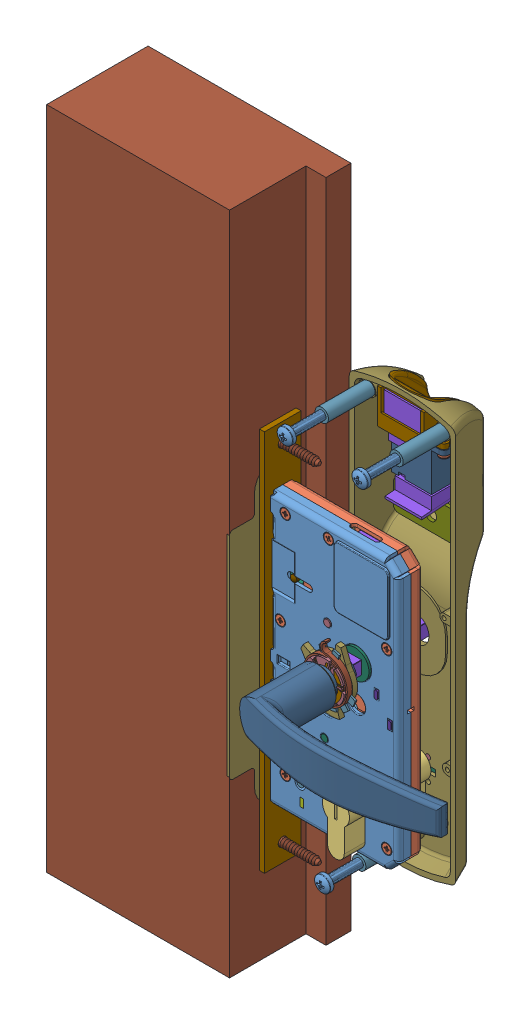
SolidWorks assembly serrure, configuration Défaut. Lengths in mm.
Overall size (189.43 263.51 140.02).
129 component instances, 74 part files, 37 mates.
Components (placement in the parent):
- porte-1: porte [Défaut] at origin size (273.47 400 77.87)
  - capteur-1: capteur [Défaut] at (-59.4622 -33.5309 -3.2336) x (0.307692 -0.951486 0) z (-0.951486 -0.307692 0) size (14.18 5.77 12.92)
    - piece26-1: piece26 [Défaut] at (1.6738 0.6186 2.775) size (12.75 5.77 7.15)
    - piece 28-1: piece 28 [Défaut] at (1.6738 0.6186 0.775) size (12.75 5.77 5.95)
    - piece27-2: piece27 [Défaut] at (-0.2012 0.6186 2.975) size (1 2.8 4.5)
    - piece29-1: piece29 [Défaut] at (-3.3489 0.6186 5.3357) x (0.986417 0 0.164259) z (-0.164259 0 0.986417) size (13.3 5.06 1.9)
  - Assemblage9-1: Assemblage9 [Défaut] at (-68.5121 32.669 3.5) x (0 1 0) z (0 0 -1) size (37.07 29 14.01)
    - Pièce31-1: Pièce31 [Défaut] at (-136.852 -20.6482 -3) size (37.07 29 6.5)
    - Assemblage8-1: Assemblage8 [Défaut] at (10.8904 0.9488 3.6462) x (0 0 1) z (0 1 0) size (12.77 25.8 12.77)
      - piece 33-1: piece 33 [Défaut] at (-0.2667 2.2913 0) size (11 9 11)
      - piece32-1: piece32 [Défaut] at (-0.2667 2.2913 0) x (-0.176766 0 0.984253) z (-0.984253 0 -0.176766) size (11 19.8 11)
    - Pièce30-1: Pièce30 [Défaut] at (-136.852 22.3518 10) x (1 0 0) z (0 0 -1) size (37.07 29 14)
  - tetiere-1: tetiere [Défaut] at (-124.6604 -27.8986 -47.7834) x (0 0 -1) z (1 0 0) size (22 230 25.2)
    - tetiere-1: tetiere [Défaut] at (-47.7834 3.4752 0) size (22 230 6)
    - Pièce37-1: Pièce37 [Défaut] at (-8.0012 83.4752 -19.368) x (1 0 0) z (0 -1 0) size (11 12 10)
    - Pièce37-2: Pièce37 [Défaut] at (-8.0012 -52.5248 -19.368) x (1 0 0) z (0 -1 0) size (11 12 10)
    - vis F90 M5-25-1: vis F90 M5-25 [PreviewCfg] at (-47.7834 107.4752 -1.3) x (0 0 1) z (-1 0 0) size (25 9.3 9.3)
    - vis F90 M5-25-2: vis F90 M5-25 [PreviewCfg] at (-47.7834 -100.5248 -1.3) x (0 0 1) z (-1 0 0) size (25 9.3 9.3)
  - Assemblage5-1: Assemblage5 [Défaut] at (-67.1198 -31.1461 -5) x (0 1 0) z (0 0 1) size (150 70 16.5)
    - Pièce20-1: Pièce20 [Défaut] at (81.7227 21.0405 -3.5) x (0 0 1) z (-1 0 0) size (14 6 6)
    - Pièce20-2: Pièce20 [Défaut] at (41.7227 -13.9595 -3.5) x (0 0 1) z (-1 0 0) size (14 6 6)
    - Pièce20-3: Pièce20 [Défaut] at (24.7227 50.0405 -3.5) x (0 0 1) z (-1 0 0) size (14 6 6)
    - Pièce20-4: Pièce20 [Défaut] at (11.2227 11.9905 -3.5) x (0 0 1) z (-0.071229 0.99746 0) size (14 6 6)
    - Pièce20-5: Pièce20 [Défaut] at (-62.2773 -13.9595 -3.5) x (0 0 1) z (-1 0 0) size (14 6 6)
    - Pièce21-1: Pièce21 [Défaut] at (37.7227 21.5405 -3.5) x (0 0 1) z (-1 0 0) size (16.4 6 6)
    - Pièce23-1: Pièce23 [Défaut] at (-54.2773 38.0405 -3.5) x (0 0 1) z (-1 0 0) size (16 6 6)
    - Pièce22-2: Pièce22 [Défaut] at (-23.2773 23.5405 -3.5) x (0 0 1) z (-0.988921 -0.148442 0) size (16 6 6)
    - Pièce24-1: Pièce24 [Défaut] at (3.7227 19.5405 3) x (-1 0 0) z (0 0 -1) size (10 9 9.5)
    - Pièce25-1: Pièce25 [Défaut] at (-74.2773 -20.9595 -0.5) size (28 10 16)
    - Pièce38-1: Pièce38 [Défaut] at (65.7227 21.0405 -3.5) x (0 0 1) z (-1 0 0) size (9 6 6)
  - Pièce18-1: Pièce18 [Défaut] at (-46.1604 57.5766 7.5) x (0 -1 0) z (0 0 -1) size (163.01 77.21 8.5)
  - vis1-1: vis1 [ISO 7046-1 - M3 x 6 - Z --- 6C] at (-114.1604 50.5766 -7.5) x (0 0 1) z (0 -1 0) size (6 5.5 5.5)
  - vis1-2: vis1 [ISO 7046-1 - M3 x 6 - Z --- 6C] at (-114.1604 -85.4234 -7.5) x (0 0 1) z (0.484646 -0.87471 0) size (6 5.5 5.5)
  - vis1-3: vis1 [ISO 7046-1 - M3 x 6 - Z --- 6C] at (-53.1604 10.5766 7.5) x (0 0 -1) z (0 1 0) size (6 5.5 5.5)
  - vis1-4: vis1 [ISO 7046-1 - M3 x 6 - Z --- 6C] at (-53.1604 -93.4234 7.5) x (0 0 -1) z (0 1 0) size (6 5.5 5.5)
  - vis1-5: vis1 [ISO 7046-1 - M3 x 6 - Z --- 6C] at (-88.1604 50.5766 7.5) x (0 0 -1) z (-0.949467 0.313867 0) size (6 5.5 5.5)
  - vis1-6: vis1 [ISO 7046-1 - M3 x 6 - Z --- 6C] at (-117.1604 -6.4234 7.5) x (0 0 -1) z (0 1 0) size (6 5.5 5.5)
  - vis1-7: vis1 [ISO 7046-1 - M3 x 6 - Z --- 6C] at (-114.1604 -85.4234 7.5) x (0 0 -1) z (0 1 0) size (6 5.5 5.5)
  - vis1-8: vis1 [ISO 7046-1 - M3 x 6 - Z --- 6C] at (-114.1604 50.5766 7.5) x (0 0 -1) z (0 1 0) size (6 5.5 5.5)
  - vis1-9: vis1 [ISO 7046-1 - M3 x 6 - Z --- 6C] at (-79.1104 -19.9234 7.5) x (0 0 -1) z (0 1 0) size (6 5.5 5.5)
  - vis2-1: vis2 [ISO 7045 - M2 x 8 - Z --- 8N] at (-61.1604 -32.4234 1.87) x (0 0 -1) z (0 1 0) size (9.57 4 4)
  - vis2-2: vis2 [ISO 7045 - M2 x 8 - Z --- 8N] at (-59.1604 -38.6081 1.87) x (0 0 -1) z (0 1 0) size (9.57 4 4)
  - vis5-1: vis5 [ISO 7046-1 - M2 x 4 - Z --- 4C] at (-78.6604 46.8507 -3.4464) x (0 0 -1) z (0.839549 0.543284 0) size (5 3.8 3.8)
  - Pièce35-1: Pièce35 [Défaut] at (-90.6604 -54.4234 0.5) x (0 1 0) z (0 0 1) size (11 11 0.5)
  - Pièce6-1: Pièce6 [Défaut] at (-90.6604 -54.4234 -2.5) x (0.802376 0.596819 0) z (0 0 1) size (8 8 3)
  - Pièce13-1: Pièce13 [Défaut] at (-59.3625 -101.9234 0) size (24 12 15)
  - Assemblage a3-2: Assemblage a3 [Défaut] at (-71.1604 89.3876 -33.9686) x (0 1 0) z (-1 0 0) size (249.51 77.87 69.84)
    - pièce a25-1: pièce a25 [Défaut] at (28.1889 -12.4686 0) size (57.24 25.6 22)
    - pièce a23-1: pièce a23 [Défaut] at (29.1889 -14.9686 0) x (-1 0 0) z (0 0 -1) size (32.42 29.23 38)
    - pièce a24-2: pièce a24 [Défaut] at (-4.8111 7.5314 0) x (0 0 1) z (1 0 0) size (42 16 26)
    - piece a27-1: piece a27 [B18.6.7M - M3 x 0.5 x 6 Type I Cross Recessed FHMS --6N] at (3.4889 -5.4686 -16.5) size (7 5.5 5.5)
    - piece a27-2: piece a27 [B18.6.7M - M3 x 0.5 x 6 Type I Cross Recessed FHMS --6N] at (3.4889 -5.4686 16.5) x (1 0 0) z (0 0 -1) size (7 5.5 5.5)
    - Assemblage a1-1: Assemblage a1 [Défaut] at (-110.8532 -13.9686 -2.8343) x (0 0 1) z (0 1 0) size (69.84 249.51 54.23)
      - piece a1-1: piece a1 [Défaut] at (2.8343 16.0422 0) size (69.84 249.51 28.23)
      - pièce a9-4: pièce a9 [Défaut] at (-3.5296 -48.0939 9) size (3 3 2)
      - pièce a9-5: pièce a9 [Défaut] at (0.505 -63.1512 9) x (-0.5 0.866025 0) z (0 0 1) size (3 3 2)
      - pièce a9-6: pièce a9 [Défaut] at (11.5277 -52.1285 9) x (-0.5 -0.866025 0) z (0 0 1) size (3 3 2)
      - pièce a8-1: pièce a8 [Défaut] at (25.3343 133.0422 8) x (0 0 -1) z (1 0 0) size (34 8 8)
      - pièce a8-2: pièce a8 [Défaut] at (-19.6657 133.0422 8) x (0 0 -1) z (1 0 0) size (34 8 8)
      - pièce a27-1: pièce a27 [Défaut] at (2.8343 -54.4578 11) size (22 22 2.5)
      - pièce a8-3: pièce a8 [Défaut] at (2.8343 -88.9578 8) x (0 0 -1) z (1 0 0) size (34 8 8)
      - pièce a26-1: pièce a26 [Défaut] at (2.8343 71.0422 17) size (45 18 2)
      - piece a20-1: piece a20 [ISO 7045 - M3 x 8 - Z --- 8N] at (-15.6657 104.0422 16.1) x (0 0 1) z (-1 0 0) size (10.35 5.6 5.6)
      - piece a20-2: piece a20 [ISO 7045 - M3 x 8 - Z --- 8N] at (21.3343 104.0422 16.1) x (0 0 1) z (-1 0 0) size (10.35 5.6 5.6)
      - piece a21-1: piece a21 [ISO 7045 - M3 x 6 - Z --- 6N] at (-15.6657 71.0422 14.6) x (0 0 1) z (-1 0 0) size (8.35 5.6 5.6)
      - piece a21-2: piece a21 [ISO 7045 - M3 x 6 - Z --- 6N] at (21.3343 71.0422 14.6) x (0 0 1) z (-1 0 0) size (8.35 5.6 5.6)
    - vis4-1: vis4 [ISO 7045 - M5 x 45 - Z --- 45N] at (22.1889 -63.6686 -22.5) x (0 1 0) z (0.065029 0 0.997883) size (48.63 9.5 9.5)
    - vis4-2: vis4 [ISO 7045 - M5 x 45 - Z --- 45N] at (22.1889 -63.6686 22.5) x (0 1 0) z (0.065029 0 0.997883) size (48.63 9.5 9.5)
    - vis4-3: vis4 [ISO 7045 - M5 x 45 - Z --- 45N] at (-199.8111 -63.6686 0) x (0 1 0) z (0.065029 0 0.997883) size (48.63 9.5 9.5)
  - porte-2: porte [Défaut] at (23.8396 10.5766 0) size (273.47 400 40) (hidden)
  - Pièce19-1: Pièce19 [Défaut] at (-46.1604 -105.4234 -7.5) x (0 1 0) z (0 0 1) size (163.01 77.21 11)
  - cylindre europeen-1: cylindre europeen [Défaut] at (-71.1604 -75.9234 -2.5) x (-1 0 0) z (0 0 -1) size (16.3 33.65 49)
  - vis F90 M5-60-1: vis F90 M5-60 [PreviewCfg] at (-125.9604 -95.4234 0) size (60 9.3 9.3)
  - axe moteur-1: axe moteur [Défaut] at (-65.5909 21.3931 -13.2202) x (-0.984609 0 -0.17477) z (0.17477 0 -0.984609) size (5.26 10.46 5.13)
  - poussoir-1: poussoir [Défaut] at (-46.1604 -106.9762 -2.2801) x (0 1 0) z (0 0 1) size (21.08 22 6)
- poignee exterieure-1: poignee exterieure [Défaut] at (0.1686 -5.7947 -1) x (0.996714 -0.081007 0) z (0 0 1) size (143.89 49.43 175.53)
  - pièce a3-1: pièce a3 [Défaut] at (-71.1604 -5.4234 -28.5) x (-1 0 0) z (0 0 -1) size (21 21 1) (hidden)
  - pièce a3-3: pièce a3 [Défaut] at (-71.1604 -5.4234 -33.5) x (0.888915 -0.458071 0) z (0 0 1) size (21 21 1) (hidden)
  - bequille-1: bequille [Défaut] at (-71.1246 -5.4081 -34) x (-0.079085 0.996868 0) z (0 0 1) size (34.63 120.11 70.52) (hidden)
  - pièce a16-1: pièce a16 [Défaut] at (-71.1246 -5.4081 -25) x (-0.999944 -0.010542 0) z (0 0 -1) size (31.16 38.76 3.06) (hidden)
  - pièce a5-1: pièce a5 [Défaut] at (-70.7945 -5.1928 -23.5) x (-0.082996 -0.99655 0) z (0 0 -1) size (33.22 26.47 3.09) (hidden)
  - pièce a7-1: pièce a7 [Défaut] at (-71.1246 -5.4081 -21.5) x (-0.986222 0.165429 0) z (0 0 -1) size (28 32 0.5) (hidden)
  - pièce a4-1: pièce a4 [Défaut] at (-71.1246 -5.4081 -18.5) x (-0.884093 0.467311 0) z (0 0 -1) size (23.6 24 3) (hidden)
  - Pièce16-1: Pièce16 [Défaut] at (-71.1246 -5.4081 -7) x (0 0 1) z (0.996868 0.079085 0) size (12.5 20 20)
  - carre-1: carre [Défaut] at (-71.1246 -5.4081 -53) x (-0.996868 -0.079085 0) z (0 0 -1) size (8.02 8 52)
  - poignee interieure-1: poignee interieure [Défaut] at (-0.6374 5.762 0) x (0.996714 0.081007 0) z (0 0 1) size (141.35 41.34 91.02)
    - pièce a3-1: pièce a3 [Défaut] at (-71.1604 -5.4234 32) size (21 21 1)
    - bequille-1: bequille [Défaut] at (-71.0969 -5.4234 32.5) x (0 -1 0) z (0 0 -1) size (34.63 120.11 70.52)
    - pièce a5-1: pièce a5 [Défaut] at (-71.9887 -5.499 25.5) x (0.053548 -0.998565 0) z (0 0 1) size (33.22 26.47 3.09)
    - pièce a16-1: pièce a16 [Défaut] at (-71.0969 -5.4234 24) x (-0.999972 -0.007518 0) z (0 0 -1) size (31.16 38.76 3.06)
    - pièce a4-1: pièce a4 [Défaut] at (-71.0969 -5.4234 28) x (0.409792 0.912179 0) z (0 0 -1) size (23.6 24 3)
    - pièce a7bis-1: pièce a7bis [Défaut] at (-71.0969 -5.4234 25) x (-0.969106 0.246645 0) z (0 0 -1) size (28 32 1)
    - pièce a3-2: pièce a3 [Défaut] at (-71.0969 -5.4234 27.5) size (21 21 1)
    - carre-1: carre [Défaut] at (-71.0969 -5.4234 51.5) size (8.02 8 52)
    - Assemblage4-1: Assemblage4 [Défaut] at (-71.1604 -5.4234 1.3) size (52.31 35.86 13.6)
      - Pièce14-1: Pièce14 [Défaut] at origin size (52.31 34.86 13.6)
      - ressort1-1: ressort1 [Défaut] at (0 11 0) x (-0.996138 0 -0.087798) z (0 1 0) size (5.8 6.7 6.99)
      - Pièce15-1: Pièce15 [Défaut] at origin size (17.38 4.41 10.6)
    - axe de noix-1: axe de noix [Défaut] at (-71.1604 0.3833 1.3) x (0 1 0) z (0 0 -1) size (15.4 6 6)
- verrouilleur-1: verrouilleur [Défaut] at (-129.1604 -27.4234 5) x (1 0 0) z (0 1 0) size (30.05 12 6)
- plaque-1: plaque [Défaut] at (-84.6824 -30.3877 5.6) x (0 -1 0) z (0 0 -1) size (115.86 55.31 11.5)
  - Pièce8-1: Pièce8 [Défaut] at (-51.9489 -2.022 0) size (115.86 54.87 2.63)
  - Pièce9-1: Pièce9 [Défaut] at (-15.5889 16.4069 10) x (0 0 -1) z (1 0 0) size (11 6 6)
  - Pièce9-2: Pièce9 [Défaut] at (60.9111 5.978 10) x (0 0 -1) z (1 0 0) size (11 6 6)
  - Pièce9-3: Pièce9 [Défaut] at (40.1491 -25.25 10) x (0 0 -1) z (0.486722 0.873557 0) size (11 6 6)
  - Pièce10-1: Pièce10 [Défaut] at (5.0511 3.978 -1.5) x (0 0 1) z (-1 0 0) size (4.5 8 8)
- pene dormant-1: pene dormant [Défaut] at (-113.0755 -51.7425 -1) x (1 0 0) z (0 0 -1) size (62 37 12)
  - Pièce11-1: Pièce11 [Défaut] at (-30.5849 -8.319 -1.5) size (62 37 9)
  - Pièce12-1: Pièce12 [Défaut] at (24.4151 -8.319 -5.5) x (0 0 1) z (-0.906877 -0.421394 0) size (12 5 5)
- pene lançant-1: pene lançant [Défaut] at (-116.6048 19.0766 -2.0131) x (1 0 0) z (0 -1 0) size (40.25 15.66 28)
  - Pièce5-1: Pièce5 [Défaut] at (-12.8916 -3.2369 -4) size (32 11 8)
  - Pièce4-1: Pièce4 [Défaut] at (-6.8916 2.2631 10.5) x (0 0 -1) z (1 0 0) size (21 6 6)
  - axe de noix-1: axe de noix [Défaut] at (7.1084 -5.2369 0) x (0 1 0) z (0 0 1) size (15.4 6 6)
  - Pièce6-1: Pièce6 [Défaut] at (7.1084 4.1631 0) x (0.982348 0 0.187064) z (0 1 0) size (8 8 3)
  - Pièce3-3: Pièce3 [Défaut] at (-6.8916 2.2631 -14) x (0.984808 -0.173648 0) z (0 0 1) size (19 11 14)
  - Pièce3-4: Pièce3 [Défaut] at (-6.8916 2.2631 14) x (0.984808 0.173648 0) z (0 0 -1) size (19 11 14)
- guide ressort-1: guide ressort [Défaut] at (-54.3814 1.7305 0) x (0 0 1) z (-0.999945 -0.010466 0) size (11 27.12 1.5)
- ressorts-1: ressorts [Défaut] at (-205.5407 -154.3869 208.4697) x (1 0 0) z (0 0 -1) size (76.49 152.32 18.47) (hidden)
  - ressort2-2: ressort2 [Défaut] at (106.6303 -126.9635 210.4697) x (0 0 1) z (1 0 0) size (6 6.93 15.69)
  - ressort3 position fermée-1: ressort3 position fermée [Défaut] at (147.4246 -79.0467 210.9697) x (0 0 -1) z (0.264302 0.96444 0) size (9.52 9.47 31.36)
  - ressort6 position fermée-2: ressort6 position fermée [Défaut] at (151.4017 -132.9478 208.4697) x (0.99055 -0.010368 -0.13676) z (-0.010466 -0.999945 0) size (8.58 8.62 23.12)
  - ressort4 position fermée-1: ressort4 position fermée [Défaut] at (117.3803 -188.9635 213.3697) x (-0.904323 -0.426848 0) z (0 0 -1) size (11.11 43.12 16.27)
  - ressort 5 position fermée-1: ressort 5 position fermée [Défaut] at (100.3803 -68.9635 212.9697) x (0.995167 0.098198 0) z (0 0 -1) size (25.36 30.87 7.5)
- chambranle-1: chambranle [Défaut] at (290.2615 1279.4527 -72.4696) size (122 400 61)
  - cadre dormant2-1: cadre dormant2 [Défaut] at (-419.4219 -1306.8762 77.4696) x (0 1 0) z (-1 0 0) size (400 61 122)
  - gache-1: gache [Défaut] at (-420.9219 -1306.8762 77.4696) x (0 -1 0) z (1 0 0) size (178.25 40 1.5)
  - vis F90 M3-25-1: vis F90 M3-25 [PreviewCfg] at (-419.4219 -1220.3762 70.9696) x (-1 0 0) z (0 1 0) size (20 5.5 5.5)
  - vis F90 M3-25-2: vis F90 M3-25 [PreviewCfg] at (-419.4219 -1286.3762 70.9696) x (-1 0 0) z (0 1 0) size (20 5.5 5.5)
  - vis F90 M3-25-3: vis F90 M3-25 [PreviewCfg] at (-419.4219 -1379.6262 70.9696) x (-1 0 0) z (0 1 0) size (20 5.5 5.5)
Mates (geometry in assembly coordinates):
- Coïncidente1: coincident anti-aligned: plane of porte-1/tetiere-1/tetiere-1 through (-126.1614 -25.4234 -5.5) normal (0 0 1); plane of verrouilleur-1 through (-121.1604 -24.4234 -5.5) normal (0 0 -1)
- Coïncidente2: coincident anti-aligned: plane of porte-1/tetiere-1/tetiere-1 through (-126.1614 -24.4234 5.5) normal (0 -1 0); plane of verrouilleur-1 through (-105.7938 -24.4234 16.2147) normal (0 1 0)
- Coïncidente4: coincident anti-aligned: plane of porte-1/tetiere-1/tetiere-1 through (-126.1614 -43.4234 3.5) normal (0 0 -1); plane of pene dormant-1/Pièce11-1 through (-143.6604 -76.4234 3.5) normal (0 0 1)
- Coïncidente5: coincident anti-aligned: plane of porte-1/tetiere-1/tetiere-1 through (-126.1614 -43.4234 2.5) normal (0 -1 0); plane of pene dormant-1/Pièce11-1 through (-122.6604 -43.4234 -5.5) normal (0 1 0)
- Coaxiale2: concentric aligned: cylinder of porte-1/Assemblage a3-2/Assemblage a1-1/piece a1-1 through (-71.1604 -5.4234 -19.999) axis (0 0 -1) radius 8; cylinder of poignee exterieure-1/Pièce16-1 through (-71.1604 -5.4234 -66.8035) axis (0 0 -1) radius 7.5
- Coïncidente12: coincident anti-aligned: plane of porte-1/tetiere-1/tetiere-1 through (-126.1614 30.0766 5.75) normal (0 0 -1); plane of pene lançant-1/Pièce5-1 through (-129.4964 15.0766 5.75) normal (0 0 1)
- Tangent2: tangent anti-aligned: cylinder of porte-1/Assemblage5-1/Pièce21-1 through (-88.6604 6.5766 7.9) axis (0 0 1) radius 2; plane of plaque-1/Pièce8-1 through (-86.6604 6.5612 5.6) normal (-1 0 0)
- Distance1: distance = 1.5 mm anti-aligned: plane of verrouilleur-1 through (-102.1604 -24.4234 1.5) normal (0 0 1); plane of plaque-1/Pièce8-1 through (-102.6505 7.1892 3) normal (0 0 -1)
- Tangent5: tangent anti-aligned: cylinder of porte-1/Assemblage5-1/Pièce22-2 through (-90.6604 -54.4234 7.5) axis (0 0 1) radius 2; plane of plaque-1/Pièce8-1 through (-88.6604 -54.4388 5.6) normal (-1 0 0)
- Tangent6: tangent: plane of plaque-1/Pièce8-1 through (-105.6604 40.9441 3) normal (-0.997564 -0.069756 0); cylinder of pene lançant-1/Pièce6-1 through (-112.1154 19.0766 5.15) axis (0 0 -1) radius 4
- Distance5: distance = 0.5 mm: line of porte-1/Assemblage5-1/Pièce25-1 through (-53.6181 -23.4234 -3) axis (0 0 1); plane of guide ressort-1 through (-54.1198 -23.2681 0) normal (0.999945 0.010466 0)
- Distance7: distance = 1 mm anti-aligned: plane of guide ressort-1 through (-55.8395 -2.2849 2) normal (0 0 1); plane of porte-1/Assemblage5-1/Pièce25-1 through (-56.6181 -21.4234 3) normal (0 0 -1)
- Tangent8: tangent anti-aligned: plane of plaque-1/Pièce8-1 through (-85.8295 -25.1448 5.6) normal (-0.669131 -0.743145 0); cylinder of pene dormant-1/Pièce12-1 through (-69.2652 -43.4234 -7.5) axis (0 0 -1) radius 2.5
- Coïncidente13: coincident anti-aligned: plane of porte-1/tetiere-1/tetiere-1 through (-126.1614 30.0766 4.75) normal (0 -1 0); plane of pene lançant-1/Pièce3-3 through (-144.3921 30.0766 3.9345) normal (0 1 0)
- Coaxiale13: concentric aligned: cylinder of plaque-1/Pièce8-1 through (-69.2652 -43.4234 5.6) axis (0 0 -1) radius 2.5; cylinder of pene dormant-1/Pièce12-1 through (-69.2652 -43.4234 -7.5) axis (0 0 -1) radius 2.5
- Coïncidente16: coincident anti-aligned: plane of verrouilleur-1 through (-106.6604 -24.4234 4) normal (-1 0 0); plane of plaque-1/Pièce8-1 through (-106.6604 -24.8759 5.6) normal (1 0 0)
- Coïncidente29: coincident aligned: line of ressorts-1/ressort2-2 through (-98.9104 -27.4234 -2) axis (1 0 0); axis of porte-1/Assemblage5-1/Pièce24-1 through (-87.6604 -27.4234 -2) axis (1 0 0)
- Coïncidente32: coincident: plane of porte-1/Assemblage5-1/Pièce24-1 through (-86.6604 -24.4234 -5.5) normal (-1 0 0); point of ressorts-1/ressort2-2
- Parallèle4: parallel aligned: plane of ressorts-1/ressort2-2 through (-86.9104 -27.4234 -4.5) normal (0 -1 0); plane of porte-1/Assemblage5-1/Pièce24-1 through (-86.6604 -24.4234 -5.5) normal (0 -1 0)
- Coïncidente33: coincident aligned: line of ressorts-1/ressort3 position fermée-1 through (-59.4324 -70.5367 -7.9276) axis (0 0 1); axis of plaque-1/Pièce9-3 through (-59.4324 -70.5367 0) axis (0 0 1)
- Coïncidente34: coincident: plane of plaque-1/Pièce9-3 through (-60.8926 -67.9161 -2) normal (0 0 1); point of ressorts-1/ressort3 position fermée-1
- Coïncidente37: coincident: plane of porte-1/Assemblage5-1/Pièce20-5 through (-55.6604 -93.4234 -7.5) normal (0 0 1); point of ressorts-1/ressort3 position fermée-1
- Coïncidente40: coincident aligned: axis of porte-1/Assemblage5-1/Pièce20-5 through (-53.1604 -93.4234 -5.5) axis (0 0 1); line of ressorts-1/ressort3 position fermée-1 through (-53.1604 -93.4234 5.9033) axis (0 0 1)
- Coïncidente43: coincident aligned: line of ressorts-1/ressort4 position fermée-1 through (-88.1604 34.5766 11.1635) axis (0 0 1); axis of porte-1/Assemblage5-1/Pièce38-1 through (-88.1604 34.5766 -5.5) axis (0 0 1)
- Tangent10: tangent anti-aligned: plane of porte-1/Assemblage5-1/Pièce20-1 through (-88.1604 50.5766 -0.5) normal (0 0 -1); cylinder of ressorts-1/ressort4 position fermée-1 through (-85.3915 51.4204 -0.9) axis (-0.337626 0.94128 0) radius 0.4
- Coïncidente48: coincident aligned: axis of porte-1/Assemblage5-1/Pièce23-1 through (-105.1604 -85.4234 -5.5) axis (0 0 1); line of ressorts-1/ressort 5 position fermée-1 through (-105.1604 -85.4234 10.1776) axis (0 0 1)
- Tangent11: tangent: cylinder of pene dormant-1/Pièce11-1 through (-120.6604 -39.4234 1.5) axis (0 -1 0) radius 1; face of ressorts-1/ressort 5 position fermée-1
- Coïncidente49: coincident anti-aligned: plane of porte-1/porte-2 through (88.5835 12.6562 -20) normal (0 0 -1); plane of chambranle-1/cadre dormant2-1 through (-117.1604 210.5766 -20) normal (0 0 1)
- Coïncidente50: coincident anti-aligned: plane of verrouilleur-1 through (-129.1604 -24.4234 5) normal (-1 0 0); plane of chambranle-1/gache-1 through (-129.1604 55.5766 -1.5) normal (1 0 0)
- Coïncidente51: coincident aligned: plane of porte-1/porte-2 through (-126.1604 210.5766 20) normal (0 1 0); plane of chambranle-1/cadre dormant2-1 through (-239.1604 210.5766 20) normal (0 1 0)
- Tangent4: tangent anti-aligned: plane of poignee exterieure-1/poignee interieure-1/Assemblage4-1/Pièce14-1 through (-103.7686 -19.3583 -3.4) normal (-0.422618 0.906308 0); cylinder of plaque-1/Pièce9-1 through (-101.0893 -14.7988 6.6) axis (0 0 1) radius 3
- Distance4: distance = 0.5 mm: line of poignee exterieure-1/poignee interieure-1/Assemblage4-1/Pièce14-1 through (-53.874 1.0226 5.6) axis (0 0 -1); plane of guide ressort-1 through (-54.1198 -23.2681 0) normal (0.999945 0.010466 0)
- Parallèle5: parallel aligned: plane of poignee exterieure-1/poignee interieure-1/Assemblage4-1/Pièce14-1 through (-71.1604 -5.4234 -5) normal (0 0 -1); plane of guide ressort-1 through (-55.8814 1.7149 -5.5) normal (0 0 -1)
- Tangent7: tangent anti-aligned: plane of poignee exterieure-1/poignee interieure-1/Assemblage4-1/Pièce14-1 through (-58.0462 1.1385 5.6) normal (0.258819 -0.965926 0); cylinder of guide ressort-1 through (-55.1064 -0.662 7.0044) axis (0 0 -1) radius 2.5
- Coaxiale14: concentric anti-aligned: cylinder of porte-1/Pièce18-1 through (-71.1604 -5.4234 -0.001) axis (0 0 1) radius 8.5; cylinder of poignee exterieure-1/poignee interieure-1/Assemblage4-1/Pièce14-1 through (-71.1604 -5.4234 8.6) axis (0 0 -1) radius 8.5
- Parallèle2: parallel anti-aligned: plane of porte-1/tetiere-1/tetiere-1 through (-123.1604 90.5766 11) normal (0 1 0); plane of poignee exterieure-1/poignee interieure-1/bequille-1
- Tangent14: tangent anti-aligned: plane of plaque-1/Pièce8-1 through (-105.6604 21.5612 3) normal (-0.997564 -0.069756 0); cylinder of pene lançant-1/Pièce6-1 through (-109.4964 19.0766 5.15) axis (0 0 -1) radius 4; line of chambranle-1/cadre dormant2-1 through (-129.1604 210.5766 -20) axis (1 0 0)
